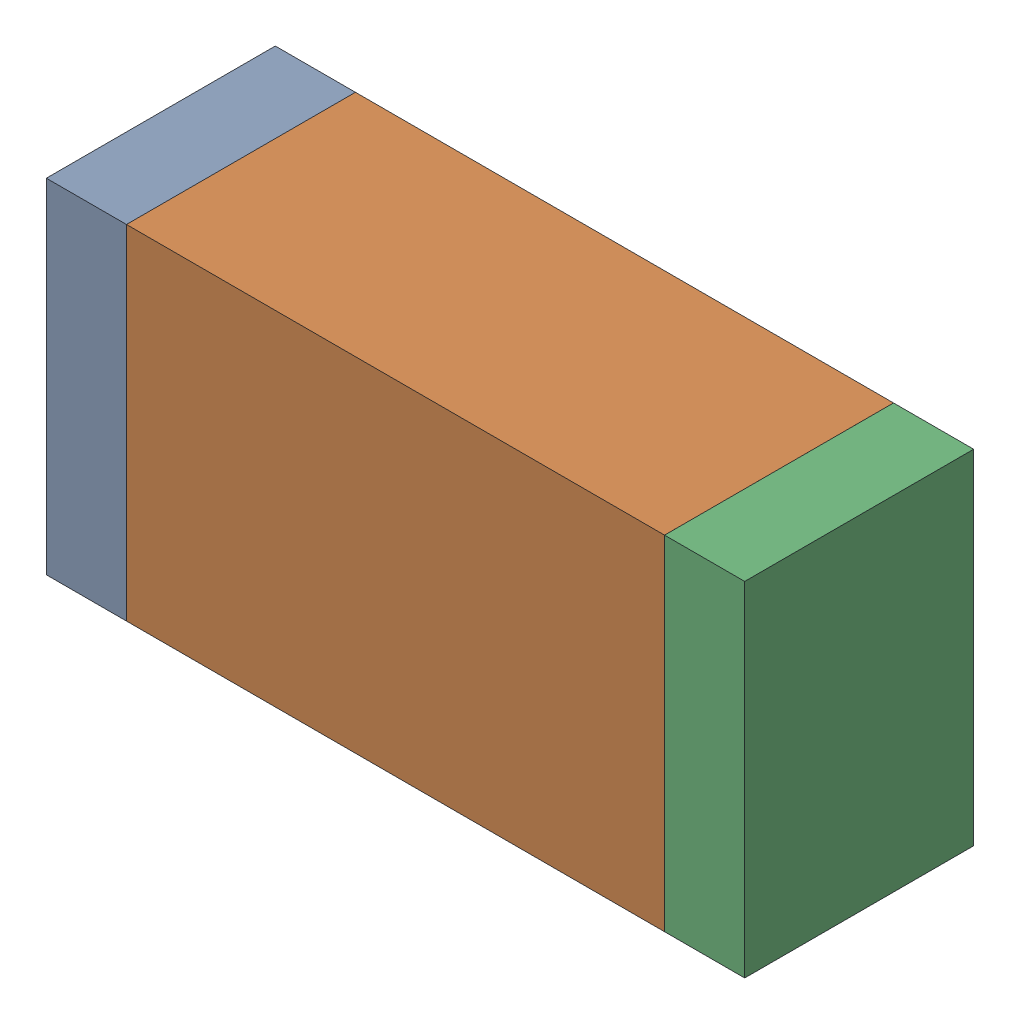
SolidWorks assembly C5, configuration Default. Lengths in mm.
Overall size (1.55 0.76 0.51).
6 component instances, 2 part files, 0 mates.
Components (placement in the parent):
- 822490216-1: 822490216 [Default] at (6.2603 1.2348 0) size (0.18 0.76 0.51)
  - Extruded-1: Extruded [Default] at origin size (0.18 0.76 0.51)
- 822498920-1: 822498920 [Default] at (6.9461 1.2348 0) size (1.19 0.76 0.51)
  - Extruded_2-1: Extruded_2 [Default] at origin size (1.19 0.76 0.51)
- 822490216-2: 822490216 [Default] at (7.6319 1.2348 0) size (0.18 0.76 0.51)
  - Extruded-1: Extruded [Default] at origin size (0.18 0.76 0.51)
